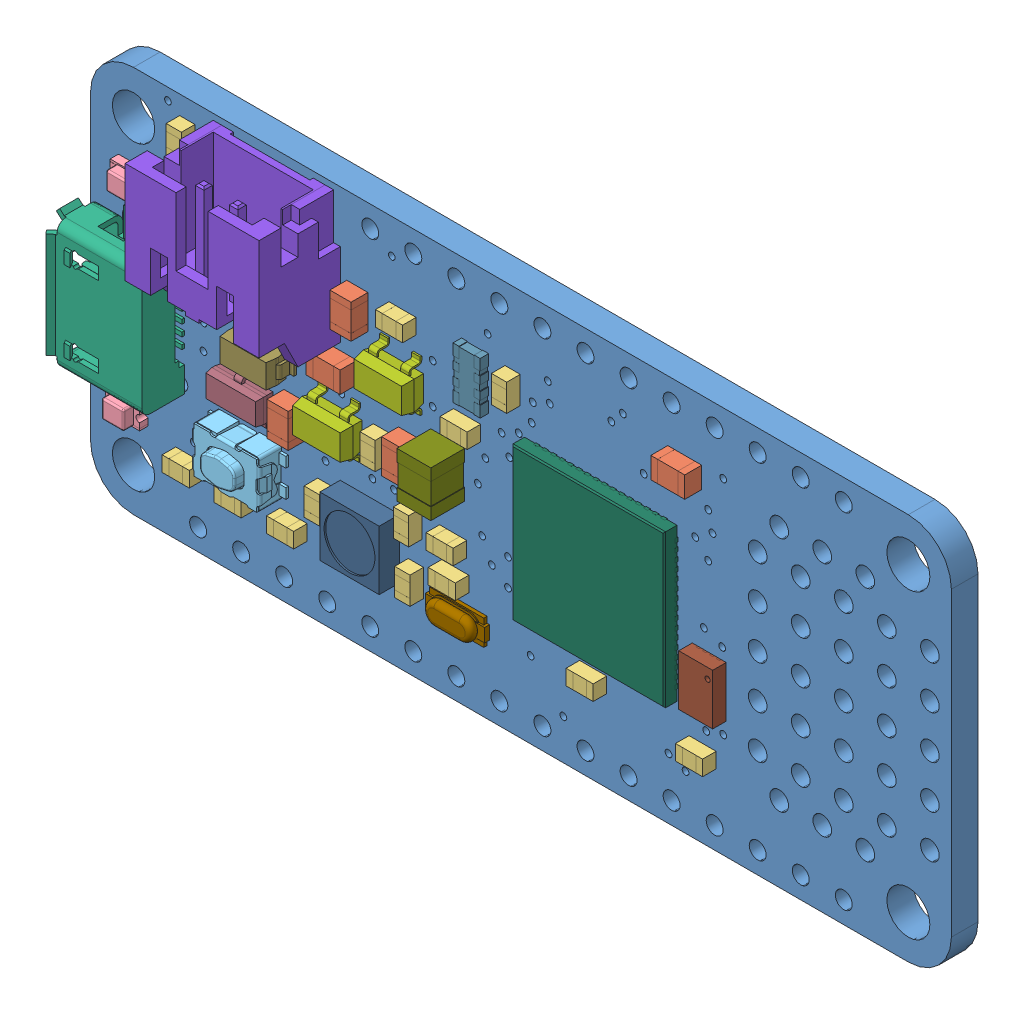
SolidWorks assembly 3857 Adafruit Feather M4 Express, configuration Default. Lengths in mm.
Overall size (50.85 22.86 6.37).
38 component instances, 16 part files, 0 mates.
Components (placement in the parent):
- 3857 Adafruit Feather M4 Express(2)^3857 Adafruit Feather M4 Express-1: 3857 Adafruit Feather M4 Express(2)^3857 Adafruit Feather M4 Express [Default] at origin size (50.85 22.86 6.37) (virtual)
  - PCB Component^3857 Adafruit Feather M4 Express(2)_3857 Adafruit Feather M4 Express-1: PCB Component^3857 Adafruit Feather M4 Express(2)_3857 Adafruit Feather M4 Express [Default] at origin size (50.85 22.86 6.37) (virtual)
    - Board^PCB Component_3857 Adafruit Feather M4 Express(2)_3857 Adafruit Feather M4 Express-1: Board^PCB Component_3857 Adafruit Feather M4 Express(2)_3857 Adafruit Feather M4 Express [Default] at origin size (50.8 22.86 1.57) (virtual)
    - 10uF^PCB Component_3857 Adafruit Feather M4 Express(2)_3857 Adafruit Feather M4 Express-1: 10uF^PCB Component_3857 Adafruit Feather M4 Express(2)_3857 Adafruit Feather M4 Express [Default] at (12.042 9.838 1.57) x (0 -1 0) z (0 0 1) size (2 1.25 1) (virtual)
    - 10uF^PCB Component_3857 Adafruit Feather M4 Express(2)_3857 Adafruit Feather M4 Express-2: 10uF^PCB Component_3857 Adafruit Feather M4 Express(2)_3857 Adafruit Feather M4 Express [Default] at (14.728 13.858 1.57) size (2 1.25 1) (virtual)
    - 10uF^PCB Component_3857 Adafruit Feather M4 Express(2)_3857 Adafruit Feather M4 Express-3: 10uF^PCB Component_3857 Adafruit Feather M4 Express(2)_3857 Adafruit Feather M4 Express [Default] at (15.748 17.272 1.57) x (0 -1 0) z (0 0 1) size (2 1.25 1) (virtual)
    - 10uF^PCB Component_3857 Adafruit Feather M4 Express(2)_3857 Adafruit Feather M4 Express-4: 10uF^PCB Component_3857 Adafruit Feather M4 Express(2)_3857 Adafruit Feather M4 Express [Default] at (35.065 18.669 1.57) size (2 1.25 1) (virtual)
    - 10uF^PCB Component_3857 Adafruit Feather M4 Express(2)_3857 Adafruit Feather M4 Express-5: 10uF^PCB Component_3857 Adafruit Feather M4 Express(2)_3857 Adafruit Feather M4 Express [Default] at (18.796 11.303 1.57) x (0 -1 0) z (0 0 1) size (2 1.25 1) (virtual)
    - 1uF^PCB Component_3857 Adafruit Feather M4 Express(2)_3857 Adafruit Feather M4 Express-1: 1uF^PCB Component_3857 Adafruit Feather M4 Express(2)_3857 Adafruit Feather M4 Express [Default] at (24.909 17.78 1.57) x (0 1 0) z (0 0 1) size (1.6 0.9 0.8) (virtual)
    - 1uF^PCB Component_3857 Adafruit Feather M4 Express(2)_3857 Adafruit Feather M4 Express-2: 1uF^PCB Component_3857 Adafruit Feather M4 Express(2)_3857 Adafruit Feather M4 Express [Default] at (11.989 4.218 1.57) size (1.6 0.9 0.8) (virtual)
    - 1uF^PCB Component_3857 Adafruit Feather M4 Express(2)_3857 Adafruit Feather M4 Express-3: 1uF^PCB Component_3857 Adafruit Feather M4 Express(2)_3857 Adafruit Feather M4 Express [Default] at (5.715 20.955 1.57) x (0 -1 0) z (0 0 1) size (1.6 0.9 0.8) (virtual)
    - 1uF^PCB Component_3857 Adafruit Feather M4 Express(2)_3857 Adafruit Feather M4 Express-4: 1uF^PCB Component_3857 Adafruit Feather M4 Express(2)_3857 Adafruit Feather M4 Express [Default] at (5.829 4.254 1.57) size (1.6 0.9 0.8) (virtual)
    - 1uF^PCB Component_3857 Adafruit Feather M4 Express(2)_3857 Adafruit Feather M4 Express-5: 1uF^PCB Component_3857 Adafruit Feather M4 Express(2)_3857 Adafruit Feather M4 Express [Default] at (18.415 17.97 1.57) size (1.6 0.9 0.8) (virtual)
    - 1uF^PCB Component_3857 Adafruit Feather M4 Express(2)_3857 Adafruit Feather M4 Express-6: 1uF^PCB Component_3857 Adafruit Feather M4 Express(2)_3857 Adafruit Feather M4 Express [Default] at (19.202 5.067 1.57) x (0 1 0) z (0 0 1) size (1.6 0.9 0.8) (virtual)
    - 1uF^PCB Component_3857 Adafruit Feather M4 Express(2)_3857 Adafruit Feather M4 Express-7: 1uF^PCB Component_3857 Adafruit Feather M4 Express(2)_3857 Adafruit Feather M4 Express [Default] at (21.526 6.35 1.57) x (-1 0 0) z (0 0 1) size (1.6 0.9 0.8) (virtual)
    - 1uF^PCB Component_3857 Adafruit Feather M4 Express(2)_3857 Adafruit Feather M4 Express-8: 1uF^PCB Component_3857 Adafruit Feather M4 Express(2)_3857 Adafruit Feather M4 Express [Default] at (36.119 4.648 1.57) x (-1 0 0) z (0 0 1) size (1.6 0.9 0.8) (virtual)
    - 1uF^PCB Component_3857 Adafruit Feather M4 Express(2)_3857 Adafruit Feather M4 Express-9: 1uF^PCB Component_3857 Adafruit Feather M4 Express(2)_3857 Adafruit Feather M4 Express [Default] at (19.126 8.065 1.57) x (0 1 0) z (0 0 1) size (1.6 0.9 0.8) (virtual)
    - 1uF^PCB Component_3857 Adafruit Feather M4 Express(2)_3857 Adafruit Feather M4 Express-10: 1uF^PCB Component_3857 Adafruit Feather M4 Express(2)_3857 Adafruit Feather M4 Express [Default] at (29.662 5.263 1.57) x (-1 0 0) z (0 0 1) size (1.6 0.9 0.8) (virtual)
    - 1uF^PCB Component_3857 Adafruit Feather M4 Express(2)_3857 Adafruit Feather M4 Express-11: 1uF^PCB Component_3857 Adafruit Feather M4 Express(2)_3857 Adafruit Feather M4 Express [Default] at (8.89 4.254 1.57) x (-1 0 0) z (0 0 1) size (1.6 0.9 0.8) (virtual)
    - 1uF^PCB Component_3857 Adafruit Feather M4 Express(2)_3857 Adafruit Feather M4 Express-12: 1uF^PCB Component_3857 Adafruit Feather M4 Express(2)_3857 Adafruit Feather M4 Express [Default] at (17.145 10.922 1.57) x (0 1 0) z (0 0 1) size (1.6 0.9 0.8) (virtual)
    - 1uF^PCB Component_3857 Adafruit Feather M4 Express(2)_3857 Adafruit Feather M4 Express-13: 1uF^PCB Component_3857 Adafruit Feather M4 Express(2)_3857 Adafruit Feather M4 Express [Default] at (13.856 6.502 1.57) x (0 -1 0) z (0 0 1) size (1.6 0.9 0.8) (virtual)
    - 1uF^PCB Component_3857 Adafruit Feather M4 Express(2)_3857 Adafruit Feather M4 Express-14: 1uF^PCB Component_3857 Adafruit Feather M4 Express(2)_3857 Adafruit Feather M4 Express [Default] at (21.4 8.065 1.57) size (1.6 0.9 0.8) (virtual)
    - 1uF^PCB Component_3857 Adafruit Feather M4 Express(2)_3857 Adafruit Feather M4 Express-15: 1uF^PCB Component_3857 Adafruit Feather M4 Express(2)_3857 Adafruit Feather M4 Express [Default] at (22.225 14.414 1.57) x (-1 0 0) z (0 0 1) size (1.6 0.9 0.8) (virtual)
    - ORANGE^PCB Component_3857 Adafruit Feather M4 Express(2)_3857 Adafruit Feather M4 Express-1: ORANGE^PCB Component_3857 Adafruit Feather M4 Express(2)_3857 Adafruit Feather M4 Express [Default] at (2.645 17.359 1.57) x (0 1 0) z (0 0 1) size (1.25 2.02 1.1) (virtual)
    - ORANGE^PCB Component_3857 Adafruit Feather M4 Express(2)_3857 Adafruit Feather M4 Express-2: ORANGE^PCB Component_3857 Adafruit Feather M4 Express(2)_3857 Adafruit Feather M4 Express [Default] at (2.413 5.588 1.57) x (0 -1 0) z (0 0 1) size (1.25 2.02 1.1) (virtual)
    - KMR2^PCB Component_3857 Adafruit Feather M4 Express(2)_3857 Adafruit Feather M4 Express-1: KMR2^PCB Component_3857 Adafruit Feather M4 Express(2)_3857 Adafruit Feather M4 Express [Default] at (9.398 6.54 1.57) x (-1 0 0) z (0 0 1) size (4.6 2.8 1.94) (virtual)
    - microUSB^PCB Component_3857 Adafruit Feather M4 Express(2)_3857 Adafruit Feather M4 Express-1: microUSB^PCB Component_3857 Adafruit Feather M4 Express(2)_3857 Adafruit Feather M4 Express [Default] at (4.445 11.43 1.57) x (0 -1 0) z (0 0 1) size (8.8 5.6 3) (virtual)
    - MCP73831T-2ACI_OT^PCB Component_3857 Adafruit Feather M4 Express(2)_3857 Adafruit Feather M4 Express-1: MCP73831T-2ACI_OT^PCB Component_3857 Adafruit Feather M4 Express(2)_3857 Adafruit Feather M4 Express [Default] at (14.732 10.922 1.57) size (3 3 1.4) (virtual)
    - MCP73831T-2ACI_OT^PCB Component_3857 Adafruit Feather M4 Express(2)_3857 Adafruit Feather M4 Express-2: MCP73831T-2ACI_OT^PCB Component_3857 Adafruit Feather M4 Express(2)_3857 Adafruit Feather M4 Express [Default] at (18.352 15.113 1.57) size (3 3 1.4) (virtual)
    - JSTPH^PCB Component_3857 Adafruit Feather M4 Express(2)_3857 Adafruit Feather M4 Express-1: JSTPH^PCB Component_3857 Adafruit Feather M4 Express(2)_3857 Adafruit Feather M4 Express [Default] at (10.795 19.304 1.57) size (7.9 8.6 4.8) (virtual)
    - 32.768^PCB Component_3857 Adafruit Feather M4 Express(2)_3857 Adafruit Feather M4 Express-1: 32.768^PCB Component_3857 Adafruit Feather M4 Express(2)_3857 Adafruit Feather M4 Express [Default] at (21.806 4.496 1.57) x (-1 0 0) z (0 0 1) size (3.5 1.5 0.8) (virtual)
    - WS2812B3535^PCB Component_3857 Adafruit Feather M4 Express(2)_3857 Adafruit Feather M4 Express-1: WS2812B3535^PCB Component_3857 Adafruit Feather M4 Express(2)_3857 Adafruit Feather M4 Express [Default] at (16.485 6.109 1.57) x (0 -1 0) z (0 0 1) size (3.5 3.5 1.2) (virtual)
    - 2MB Flash^PCB Component_3857 Adafruit Feather M4 Express(2)_3857 Adafruit Feather M4 Express-1: 2MB Flash^PCB Component_3857 Adafruit Feather M4 Express(2)_3857 Adafruit Feather M4 Express [Default] at (36.512 8.433 1.57) x (0 1 0) z (0 0 1) size (3 2 0.8) (virtual)
    - MBR120^PCB Component_3857 Adafruit Feather M4 Express(2)_3857 Adafruit Feather M4 Express-1: MBR120^PCB Component_3857 Adafruit Feather M4 Express(2)_3857 Adafruit Feather M4 Express [Default] at (10.35 12.319 1.57) x (-1 0 0) z (0 0 1) size (3.6 1.4 1.35) (virtual)
    - DMG341^PCB Component_3857 Adafruit Feather M4 Express(2)_3857 Adafruit Feather M4 Express-1: DMG341^PCB Component_3857 Adafruit Feather M4 Express(2)_3857 Adafruit Feather M4 Express [Default] at (9.398 9.842 1.57) size (3.04 2.64 1.12) (virtual)
    - 100K^PCB Component_3857 Adafruit Feather M4 Express(2)_3857 Adafruit Feather M4 Express-1: 100K^PCB Component_3857 Adafruit Feather M4 Express(2)_3857 Adafruit Feather M4 Express [Default] at (22.67 17.208 1.57) x (0 1 0) z (0 0 1) size (3.05 1.6 0.5) (virtual)
    - ATSAMD51J^PCB Component_3857 Adafruit Feather M4 Express(2)_3857 Adafruit Feather M4 Express-1: ATSAMD51J^PCB Component_3857 Adafruit Feather M4 Express(2)_3857 Adafruit Feather M4 Express [Default] at (30.162 11.049 1.57) x (0 1 0) z (0 0 1) size (9 9 0.8) (virtual)
    - 10uH^PCB Component_3857 Adafruit Feather M4 Express(2)_3857 Adafruit Feather M4 Express-1: 10uH^PCB Component_3857 Adafruit Feather M4 Express(2)_3857 Adafruit Feather M4 Express [Default] at (21.082 11.811 1.57) x (0 -1 0) z (0 0 1) size (2.7 2 2) (virtual)
